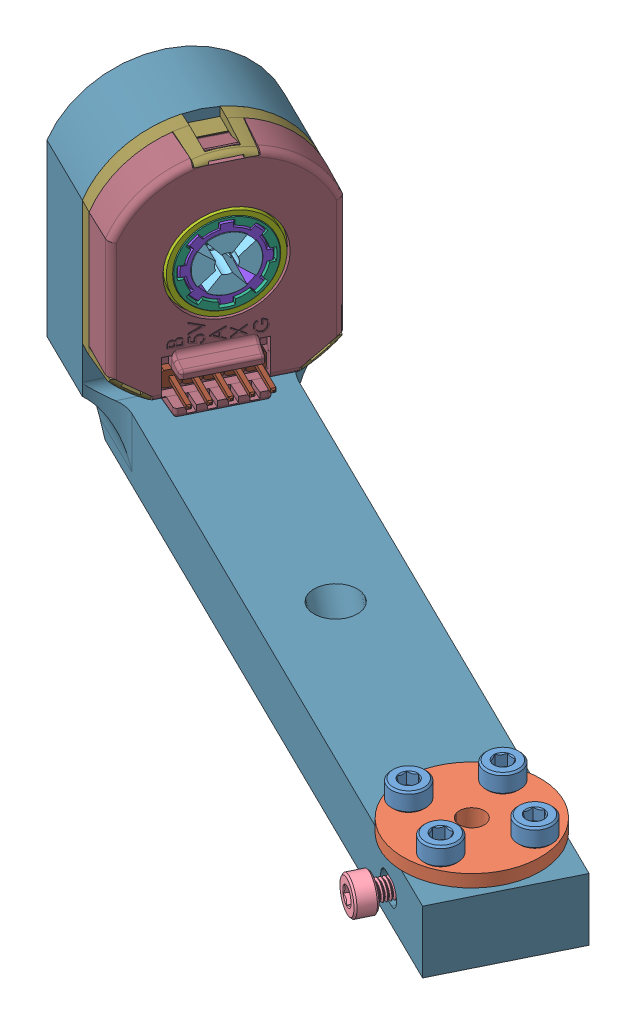
SolidWorks assembly arm1_assembly, configuration Default. Lengths in mm.
Overall size (121.02 49.68 80.08).
22 component instances, 15 part files, 13 mates.
Components (placement in the parent):
- M3-12-1: M3-12 [90037A105] at (210.6163 363.5458 144.2814) x (0.9103 0 -0.41395) z (0 -1 0) size (5.5 5.5 15.23)
- M4 Shaft Coupler-1: M4 Shaft Coupler [Default] at (208.0367 375.5458 136.7087) x (0.946589 0 -0.322442) z (0 -1 0) size (22 22 12)
- M3 Nut-1: M3 Nut [91828A211] at (210.6163 364.8058 144.2814) x (-0.322442 0 -0.946589) z (0 1 0) size (5.5 6.35 2.78)
- M3-10-1: M3-10 [90037A105] at (207.1541 368.0458 138.5033) x (0.569055 0.773205 0.279878) z (0.441339 0 -0.897341) size (5.5 5.5 13.21)
- CUI_DEVICES_CUI_DEVICES_AMT103-D0048-I3000-S-1: CUI_DEVICES_CUI_DEVICES_AMT103-D0048-I3000-S [Default] at (125.7237 394.9175 96.2247) x (0.441339 0 -0.897341) z (0.897341 0 0.441339) size (36.33 37.04 14.49)
  - CUI_DEVICES_AMT-Sleeve-REV-D(3 mm)-1: CUI_DEVICES_AMT-Sleeve-REV-D(3 mm) [Default] at (0 0 -2.42) x (0.999996 0.002864 0) z (0 0 1) size (10.79 10.79 7.8)
  - CUI_DEVICES_AMT-Hub-Top-REV-D1-1: CUI_DEVICES_AMT-Hub-Top-REV-D1 [Default] at (0 0 2.13) x (0.999996 0.002864 0) z (0 0 1) size (14 14 5.67)
  - CUI_DEVICES_AMT-Hub-Bottom-REV-B-1: CUI_DEVICES_AMT-Hub-Bottom-REV-B [Default] at (0 0 2.43) x (0.999998 -0.001942 0) z (0 0 1) size (17.3 17.3 3.2)
  - CUI_DEVICES_AMT10X-Shaft-Adaptor-REV-E-1: CUI_DEVICES_AMT10X-Shaft-Adaptor-REV-E [Default] at (0 0 0.03) x (0.999996 0.002864 0) z (0 0 1) size (11.8 11.8 7.8)
  - CUI_DEVICES_Receiver-board-1: CUI_DEVICES_Receiver-board [Default] at (72.2834 -20.351 3.03) x (-1 0 0) z (0 0 -1) size (26.5 26.62 0.41)
  - CUI_DEVICES_Rotor-board-REV F-1: CUI_DEVICES_Rotor-board-REV F [Default] at (0 0 2.13) x (0.807874 -0.589355 0) z (0 0 1) size (26 26 0.3)
  - CUI_DEVICES_Transmitter-board AMT10(AMT-103)-1: CUI_DEVICES_Transmitter-board AMT10(AMT-103) [Default] at (19.1596 -17.1102 1.22) x (-1 0 0) z (0 0 -1) size (26.63 29.61 12.1)
  - CUI_DEVICES_AMT-103-Base-REV-K(Default)-1: CUI_DEVICES_AMT-103-Base-REV-K(Default) [Default] at (0 0 -1) x (-1 0 0) z (0 0 -1) size (28.59 34.62 9.11)
  - CUI_DEVICES_AMT-103-Top-Cover-REV-I-1: CUI_DEVICES_AMT-103-Top-Cover-REV-I [Default] at (0 0 5.23) x (-1 0 0) z (0 0 -1) size (28.6 33.94 9.26)
- Copy of Part2^arm1_assembly-2: Copy of Part2^arm1_assembly [Default] at (151.0229 411.3901 36.2435) x (-0.441339 0 0.897341) z (-0.897341 0 -0.441339) size (30.22 46.82 120) (virtual)
- 8mm_bearing-1: 8mm_bearing [Default] at (114.6236 394.9175 90.7653) x (-0.114745 -0.965611 0.233302) z (-0.426161 0.259993 0.866482) size (22 7 22)
- M3-12-2: M3-12 [90037A105] at (200.464 363.5458 139.2882) x (0.41395 0 0.9103) z (0 -1 0) size (5.5 5.5 15.23)
- M3-12-3: M3-12 [90037A105] at (205.4572 363.5458 129.1359) x (-0.9103 0 0.41395) z (0 -1 0) size (5.5 5.5 15.23)
- M3-12-4: M3-12 [90037A105] at (215.6095 363.5458 134.1291) x (-0.41395 0 -0.9103) z (0 -1 0) size (5.5 5.5 15.23)
- M3 Nut-2: M3 Nut [91828A211] at (200.464 364.8058 139.2882) x (0.946589 0 -0.322442) z (0 1 0) size (5.5 6.35 2.78)
- M3 Nut-3: M3 Nut [91828A211] at (205.4572 364.8058 129.1359) x (0.322442 0 0.946589) z (0 1 0) size (5.5 6.35 2.78)
- M3 Nut-4: M3 Nut [91828A211] at (215.6095 364.8058 134.1291) x (-0.946589 0 0.322442) z (0 1 0) size (5.5 6.35 2.78)
Mates (geometry in assembly coordinates):
- Coincident37: coincident anti-aligned: plane of M4 Shaft Coupler-1 through (208.0367 375.5458 136.7087) normal (0 1 0); plane of M3-12-1 through (210.6163 375.5458 144.2814) normal (0 -1 0)
- Concentric288: concentric aligned: circle of M4 Shaft Coupler-1; cylinder of M3-12-1 through (210.6163 378.5458 144.2814) axis (0 -1 0) radius 2.75
- Concentric289: concentric aligned: cylinder of M3-12-1 through (210.6163 378.5458 144.2814) axis (0 -1 0) radius 2.75; circle of M3 Nut-1
- Coincident39: coincident anti-aligned: plane of M4 Shaft Coupler-1 through (208.0367 375.5458 136.7087) normal (0.946589 0 -0.322442); plane of M3 Nut-1 through (210.6163 364.8058 144.2814) normal (-0.946589 0 0.322442)
- Tangent1: tangent anti-aligned: cylinder of M4 Shaft Coupler-1 through (208.0367 363.5458 136.7087) axis (0 1 0) radius 2; plane of M3-10-1 through (207.1541 368.0458 138.5033) normal (0.441339 0 -0.897341)
- Lock1: lock: unknown of CUI_DEVICES_CUI_DEVICES_AMT103-D0048-I3000-S-1/CUI_DEVICES_AMT-103-Base-REV-K(Default)-1; unknown of Copy of Part2^arm1_assembly-2
- Concentric290: concentric anti-aligned: cylinder of CUI_DEVICES_CUI_DEVICES_AMT103-D0048-I3000-S-1/CUI_DEVICES_AMT-103-Top-Cover-REV-I-1 through (124.5841 394.9175 95.6642) axis (0.897341 0 0.441339) radius 7.65; cylinder of 8mm_bearing-1 through (114.6236 394.9175 90.7653) axis (-0.897341 0 -0.441339) radius 4
- Coincident42: coincident anti-aligned: plane of Copy of Part2^arm1_assembly-2 through (117.7643 394.9175 92.31) normal (-0.897341 0 -0.441339); plane of 8mm_bearing-1 through (116.5021 384.2957 94.8763) normal (0.897341 0 0.441339)
- Concentric291: concentric aligned: cylinder of M4 Shaft Coupler-1 through (208.0367 363.5458 136.7087) axis (0 1 0) radius 5; cylinder of Copy of Part2^arm1_assembly-2 through (208.0367 363.5458 136.7087) axis (0 1 0) radius 5.2
- Coincident43: coincident anti-aligned: plane of M4 Shaft Coupler-1 through (208.0367 373.5458 136.7087) normal (0 -1 0); plane of Copy of Part2^arm1_assembly-2 through (223.2182 373.5458 133.0313) normal (0 1 0)
- Coincident44: coincident: plane of M4 Shaft Coupler-1 through (208.0367 375.5458 136.7087) normal (0.946589 0 -0.322442); line of Copy of Part2^arm1_assembly-2 through (208.0367 373.5458 136.7087) axis (0.322442 0 0.946589)
- Coincident46: coincident anti-aligned: plane of M3 Nut-1 through (210.0001 366.0058 147.3964) normal (0 1 0); plane of Copy of Part2^arm1_assembly-2 through (151.0229 366.0058 36.2435) normal (0 -1 0)
- Concentric293: concentric anti-aligned: cylinder of M4 Shaft Coupler-1 through (214.9024 368.0458 122.7493) axis (-0.441339 0 0.897341) radius 1.5; cylinder of M3-10-1 through (201.4167 368.0458 150.1688) axis (0.441339 0 -0.897341) radius 2.75
